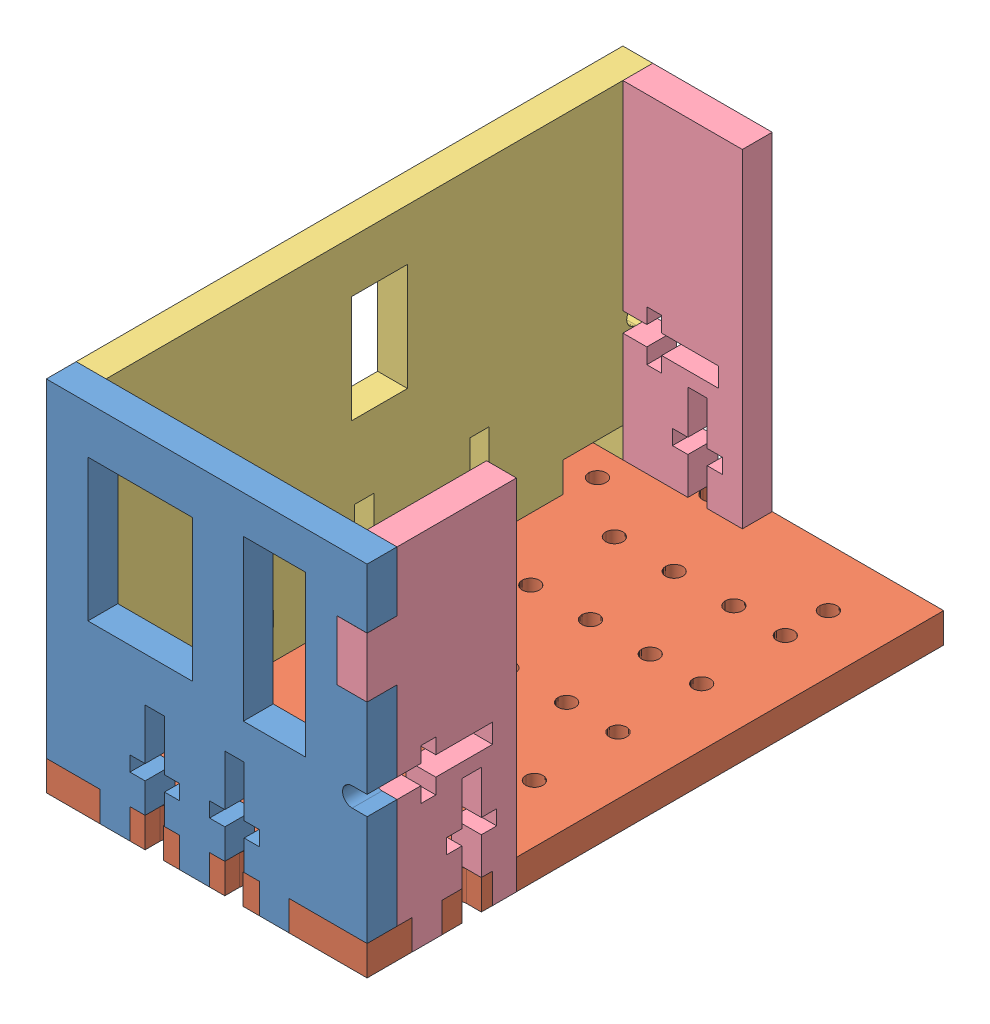
SolidWorks assembly DemoAssemblyForBoardStackv1, configuration Default. Lengths in mm.
Overall size (81.97 76.22 122.58).
6 component instances, 4 part files, 0 mates.
Components (placement in the parent):
- DemoAssemblyForBoardStackv1.STEP-1: DemoAssemblyForBoardStackv1.STEP [Default] at origin size (81.97 76.22 122.58)
  - StackBackWall.STEP-1: StackBackWall.STEP [Default] at (7.3434 2.5857 65.0269) size (68.2 76.2 6.35)
  - StackUpperLayer.STEP-1: StackUpperLayer.STEP [Default] at (102.7332 -35.5143 10.0881) x (1 0 0) z (0 1 0) size (81.97 122.58 6.35)
  - StackSideWall.STEP-1: StackSideWall.STEP [Default] at (-20.4075 2.5857 6.9131) x (0 0 1) z (-1 0 0) size (116.23 76.2 6.35)
  - BackWallSupport.STEP-1: BackWallSupport.STEP [Default] at (35.0944 -29.1796 65.0269) x (0 0 -1) z (1 0 0) size (31.75 76.2 6.35)
  - BackWallSupport.STEP-2: BackWallSupport.STEP [Default] at (-20.4075 -29.1643 -51.2006) size (31.75 76.2 6.35)
